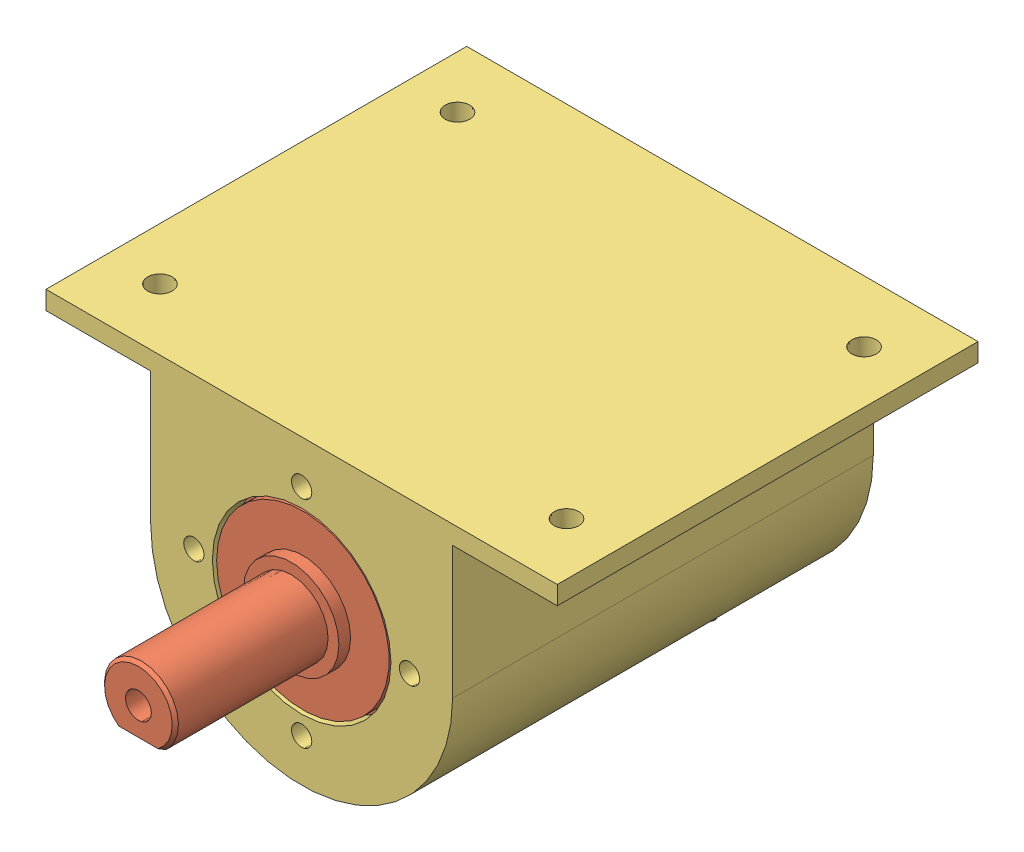
SolidWorks assembly Assemblage Total moteur-cache, configuration Défaut. Lengths in mm.
Overall size (83 52 94.8).
4 component instances, 3 part files, 3 mates.
Components (placement in the parent):
- Assemblage Moteur-réducteur Faulhaber-1: Assemblage Moteur-réducteur Faulhaber [Défaut] at (2.5405 0.6017 16.3513) size (42 48.5 94.7)
  - 4221G_BXTH _ moteur-1: 4221G_BXTH _ moteur [Défaut] at (-4.2788 3.5509 53) size (42 48.5 35)
  - 42gpt-2stage_standard+KSx _ reducteur-1: 42gpt-2stage_standard+KSx _ reducteur [Défaut] at (-138.2788 3.5509 53) size (42 42.04 72.7)
- Cache moteur-1: Cache moteur [Défaut] at (-1.7383 4.1526 112.5513) x (1 0 0) z (0 0 -1) size (83 49 68.3)
Mates (geometry in assembly coordinates):
- Coïncidente2: coincident anti-aligned: plane of Assemblage Moteur-réducteur Faulhaber-1/42gpt-2stage_standard+KSx _ reducteur-1 through (-1.7383 4.1526 112.5513) normal (0 0 1); plane of Cache moteur-1 through (-1.7383 4.1526 112.5513) normal (0 0 -1)
- Coaxiale1: concentric anti-aligned: circle of Assemblage Moteur-réducteur Faulhaber-1/42gpt-2stage_standard+KSx _ reducteur-1; circle of Cache moteur-1
- Coaxiale2: concentric anti-aligned: circle of Assemblage Moteur-réducteur Faulhaber-1/42gpt-2stage_standard+KSx _ reducteur-1; circle of Cache moteur-1
